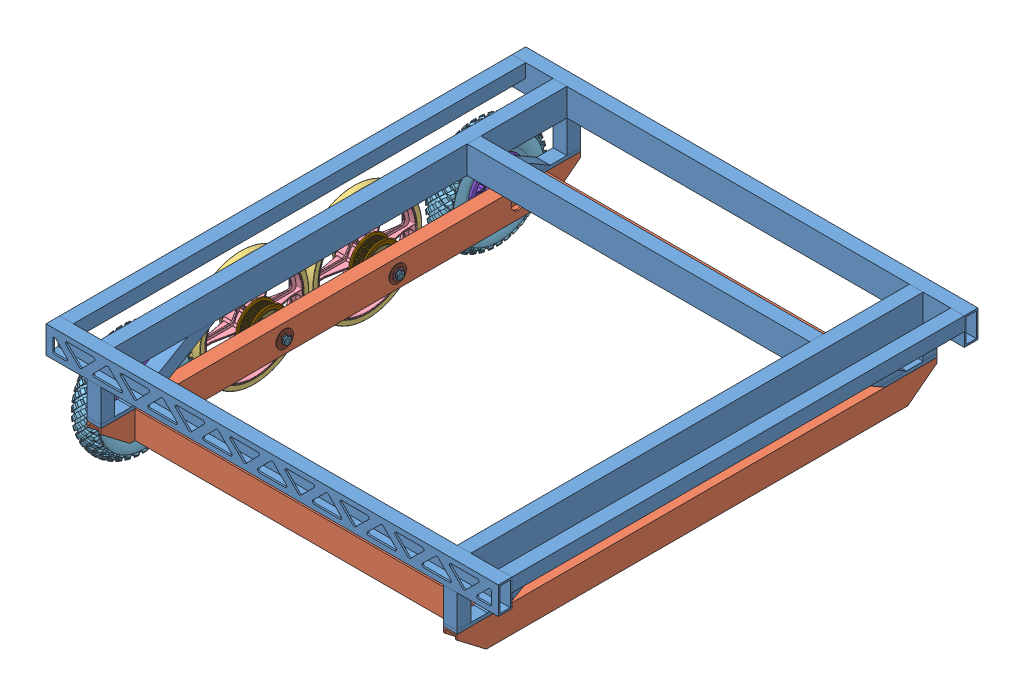
SolidWorks assembly Assem1, configuration Default. Lengths in mm.
Overall size (838.2 282.45 889).
61 component instances, 15 part files, 87 mates.
Components (placement in the parent):
- Frame-1: Frame [Default<As Machined>] at origin size (838.2 117.47 889)
- Frame_Lower-1: Frame_Lower [Default<As Machined>] at (0 -117.475 0) size (685.8 50.8 889)
- 8Inch_Wheel-1: 8Inch_Wheel [Default] at (-372.5037 -117.475 -104.775) x (0 -0.866025 -0.5) z (-1 0 0) size (204.35 204.35 38.11)
  - 2010 8 tread-1: 2010 8 tread [Default] at (0 0 12.7) size (204.35 204.35 25.4)
  - 2010 8 hub-1: 2010 8 hub [Default] at origin size (190.5 190.5 38.11)
- 8Inch_Pneumatic_Wheel-1: 8Inch_Pneumatic_Wheel [Default] at (-363.7926 -119.2955 -326.2593) x (1 0 0) z (0 1 0) size (54.46 203.4 203.4)
  - Tire-1: Tire [Default] at (-14.0642 3.9407 4.9955) x (0 0 1) z (-1 0 0) size (203.4 203.4 50.81)
  - Valve-1: Valve [Default] at (-14.5404 48.2951 4.9955) x (0 1 0) z (0 0 1) size (16.51 34.98 12.8)
  - Pneumatic Hub-1: Pneumatic Hub [Default] at (-8.6594 5.0758 -4.0835) size (45.47 106.55 106.55)
    - #4x1.00, Plastic Thread Rolling Screw, Pan Head, Cross Recessed, Zinc Plated (Plastic Applications)_-1: #4x1.00, Plastic Thread Rolling Screw, Pan Head, Cross Recessed, Zinc Plated (Plastic Applications)_ [Default] at (7.3269 34.0601 29.3991) x (-1 0 0) z (0 -0.924225 -0.381849) size (27.43 5.56 5.56)
    - Hub-1: Hub [Default] at (-28.6141 -1.1351 9.0791) size (25.79 106.55 106.55)
    - #4x1.00, Plastic Thread Rolling Screw, Pan Head, Cross Recessed, Zinc Plated (Plastic Applications)_-2: #4x1.00, Plastic Thread Rolling Screw, Pan Head, Cross Recessed, Zinc Plated (Plastic Applications)_ [Default] at (7.3269 -1.1351 -31.5609) x (-1 0 0) z (0 0.131421 0.991327) size (27.43 5.56 5.56)
    - #4x1.00, Plastic Thread Rolling Screw, Pan Head, Cross Recessed, Zinc Plated (Plastic Applications)_-3: #4x1.00, Plastic Thread Rolling Screw, Pan Head, Cross Recessed, Zinc Plated (Plastic Applications)_ [Default] at (-19.0891 -1.1351 49.7191) x (1 0 0) z (0 -0.750107 0.661316) size (27.43 5.56 5.56)
    - #4x1.00, Plastic Thread Rolling Screw, Pan Head, Cross Recessed, Zinc Plated (Plastic Applications)_-4: #4x1.00, Plastic Thread Rolling Screw, Pan Head, Cross Recessed, Zinc Plated (Plastic Applications)_ [Default] at (7.3269 -36.3304 29.3991) x (-1 0 0) z (0 0.792804 -0.609477) size (27.43 5.56 5.56)
    - #4x1.00, Plastic Thread Rolling Screw, Pan Head, Cross Recessed, Zinc Plated (Plastic Applications)_-5: #4x1.00, Plastic Thread Rolling Screw, Pan Head, Cross Recessed, Zinc Plated (Plastic Applications)_ [Default] at (-19.0891 34.0601 -11.2409) x (1 0 0) z (0 0.94777 0.318954) size (27.43 5.56 5.56)
    - #4x1.00, Plastic Thread Rolling Screw, Pan Head, Cross Recessed, Zinc Plated (Plastic Applications)_-6: #4x1.00, Plastic Thread Rolling Screw, Pan Head, Cross Recessed, Zinc Plated (Plastic Applications)_ [Default] at (-19.0891 -36.3304 -11.2409) x (1 0 0) z (0 -0.197663 -0.98027) size (27.43 5.56 5.56)
    - Hub-2: Hub [Default] at (16.8519 -1.1351 9.0791) x (-1 0 0) z (0 0 -1) size (25.79 106.55 106.55)
- 8Inch_Pneumatic_Wheel-2: 8Inch_Pneumatic_Wheel [Default] at (-359.7159 -119.2955 334.1407) x (1 0 0) z (0 1 0) size (54.46 203.4 203.4)
  - Tire-1: Tire [Default] at (-14.0642 3.9407 4.9955) x (0 0 1) z (-1 0 0) size (203.4 203.4 50.81)
  - Valve-1: Valve [Default] at (-14.5404 48.2951 4.9955) x (0 1 0) z (0 0 1) size (16.51 34.98 12.8)
  - Pneumatic Hub-1: Pneumatic Hub [Default] at (-8.6594 5.0758 -4.0835) size (45.47 106.55 106.55)
    - #4x1.00, Plastic Thread Rolling Screw, Pan Head, Cross Recessed, Zinc Plated (Plastic Applications)_-1: #4x1.00, Plastic Thread Rolling Screw, Pan Head, Cross Recessed, Zinc Plated (Plastic Applications)_ [Default] at (7.3269 34.0601 29.3991) x (-1 0 0) z (0 -0.924225 -0.381849) size (27.43 5.56 5.56)
    - Hub-1: Hub [Default] at (-28.6141 -1.1351 9.0791) size (25.79 106.55 106.55)
    - #4x1.00, Plastic Thread Rolling Screw, Pan Head, Cross Recessed, Zinc Plated (Plastic Applications)_-2: #4x1.00, Plastic Thread Rolling Screw, Pan Head, Cross Recessed, Zinc Plated (Plastic Applications)_ [Default] at (7.3269 -1.1351 -31.5609) x (-1 0 0) z (0 0.131421 0.991327) size (27.43 5.56 5.56)
    - #4x1.00, Plastic Thread Rolling Screw, Pan Head, Cross Recessed, Zinc Plated (Plastic Applications)_-3: #4x1.00, Plastic Thread Rolling Screw, Pan Head, Cross Recessed, Zinc Plated (Plastic Applications)_ [Default] at (-19.0891 -1.1351 49.7191) x (1 0 0) z (0 -0.750107 0.661316) size (27.43 5.56 5.56)
    - #4x1.00, Plastic Thread Rolling Screw, Pan Head, Cross Recessed, Zinc Plated (Plastic Applications)_-4: #4x1.00, Plastic Thread Rolling Screw, Pan Head, Cross Recessed, Zinc Plated (Plastic Applications)_ [Default] at (7.3269 -36.3304 29.3991) x (-1 0 0) z (0 0.792804 -0.609477) size (27.43 5.56 5.56)
    - #4x1.00, Plastic Thread Rolling Screw, Pan Head, Cross Recessed, Zinc Plated (Plastic Applications)_-5: #4x1.00, Plastic Thread Rolling Screw, Pan Head, Cross Recessed, Zinc Plated (Plastic Applications)_ [Default] at (-19.0891 34.0601 -11.2409) x (1 0 0) z (0 0.94777 0.318954) size (27.43 5.56 5.56)
    - #4x1.00, Plastic Thread Rolling Screw, Pan Head, Cross Recessed, Zinc Plated (Plastic Applications)_-6: #4x1.00, Plastic Thread Rolling Screw, Pan Head, Cross Recessed, Zinc Plated (Plastic Applications)_ [Default] at (-19.0891 -36.3304 -11.2409) x (1 0 0) z (0 -0.197663 -0.98027) size (27.43 5.56 5.56)
    - Hub-2: Hub [Default] at (16.8519 -1.1351 9.0791) x (-1 0 0) z (0 0 -1) size (25.79 106.55 106.55)
- 8Inch_Wheel-2: 8Inch_Wheel [Default] at (-372.5037 -117.475 104.775) x (0 -0.866025 -0.5) z (-1 0 0) size (204.35 204.35 38.11)
  - 2010 8 tread-1: 2010 8 tread [Default] at (0 0 12.7) size (204.35 204.35 25.4)
  - 2010 8 hub-1: 2010 8 hub [Default] at origin size (190.5 190.5 38.11)
- 2.6Inch_Plastic_Pulley-1: 2.6Inch_Plastic_Pulley [Default] at (-367.1697 -117.475 104.775) x (1 0 0) z (0 -0.5 0.866025) size (23.46 74.23 74.23)
  - am-2234_2.6Inch_Plastic_Pulley-1: am-2234_2.6Inch_Plastic_Pulley [Default] at origin size (13 74.23 74.23)
  - am-2234_2.6Inch_Plastic_Pulley-2: am-2234_2.6Inch_Plastic_Pulley [Default] at (16.6624 0 0) x (-1 0 0) z (0 0.000084 1) size (13 74.23 74.23)
- am-0277_16Tooth_Sprocket-1: am-0277_16Tooth_Sprocket [Default] at (-334.137 -117.475 104.775) x (0 0.811515 -0.584332) z (-1 0 0) size (35.21 35.21 10.86)
- 1.125Inch_Flange_Bearing-1: 1.125Inch_Flange_Bearing [Default] at (-315.9252 -117.475 104.775) x (0 0.899836 0.436228) z (0 -0.436228 0.899836) size (31.12 7.92 31.12)
- 1.125Inch_Flange_Bearing-2: 1.125Inch_Flange_Bearing [Default] at (-344.4748 -117.475 104.775) x (0 0.899836 -0.436228) z (0 -0.436228 -0.899836) size (31.12 7.92 31.12)
- am-0096a_Hex_Hub-1: am-0096a_Hex_Hub [Default] at (-390.3296 -117.475 104.775) size (25.4 57.15 57.15)
- 1.125Inch_Flange_Bearing-3: 1.125Inch_Flange_Bearing [Default] at (-315.9252 -117.475 -104.775) x (0 0.899836 0.436228) z (0 -0.436228 0.899836) size (31.12 7.92 31.12)
- am-0277_16Tooth_Sprocket-2: am-0277_16Tooth_Sprocket [Default] at (-334.137 -117.475 -104.775) x (0 0.911804 0.410626) z (-1 0 0) size (35.21 35.21 10.86)
- 1.125Inch_Flange_Bearing-4: 1.125Inch_Flange_Bearing [Default] at (-344.4748 -117.475 -104.775) x (0 0.072133 -0.997395) z (0 -0.997395 -0.072133) size (31.12 7.92 31.12)
- am-0096a_Hex_Hub-2: am-0096a_Hex_Hub [Default] at (-365.4474 -117.475 -104.775) x (-1 0 0) z (0 0 -1) size (25.4 57.15 57.15)
- 2.6Inch_Plastic_Pulley-2: 2.6Inch_Plastic_Pulley [Default] at (-367.1697 -117.4742 -104.7754) x (1 0 0) z (0 -0.500018 0.866015) size (23.46 74.23 74.23)
  - am-2234_2.6Inch_Plastic_Pulley-1: am-2234_2.6Inch_Plastic_Pulley [Default] at origin size (13 74.23 74.23)
  - am-2234_2.6Inch_Plastic_Pulley-2: am-2234_2.6Inch_Plastic_Pulley [Default] at (16.6624 0 0) x (-1 0 0) z (0 0.000084 1) size (13 74.23 74.23)
- 0.5Inch_Hex_Bearing_Washer-1: 0.5Inch_Hex_Bearing_Washer [Default] at (-346.0623 -117.475 -104.775) x (0 -0.5 0.866025) z (1 0 0) size (19.51 19.51 1.59)
- am-0096a_Hex_Hub-3: am-0096a_Hex_Hub [Default] at (-390.3296 -117.475 -104.775) x (1 0 0) z (0 0.866025 0.5) size (25.4 57.15 57.15)
- 5Inch_Hex_Shaft-2: 5Inch_Hex_Shaft [Default] at (-310.3372 -117.475 -104.775) x (0 -1 0) z (-1 0 0) size (14.66 12.7 103.19)
- 0.5Inch_Hex_Bearing_Washer-2: 0.5Inch_Hex_Bearing_Washer [Default] at (-315.9252 -117.475 -104.775) x (0 1 0) z (1 0 0) size (19.51 19.51 1.59)
- am-0096a_Hex_Hub-4: am-0096a_Hex_Hub [Default] at (-365.4474 -117.475 104.775) x (-1 0 0) z (0 -0.866025 -0.5) size (25.4 57.15 57.15)
- 0.5Inch_Hex_Bearing_Washer-3: 0.5Inch_Hex_Bearing_Washer [Default] at (-346.0623 -117.475 104.775) x (0 1 0) z (1 0 0) size (19.51 19.51 1.59)
- 5Inch_Hex_Shaft-3: 5Inch_Hex_Shaft [Default] at (-310.3372 -117.475 104.775) x (0 -1 0) z (-1 0 0) size (14.66 12.7 103.19)
- 5Inch_Hex_Shaft-4: 5Inch_Hex_Shaft [Default] at (-303.0728 -114.3 330.2) x (0 0.866025 0.5) z (-1 0 0) size (14.66 12.7 103.19)
- 1.125Inch_Flange_Bearing-5: 1.125Inch_Flange_Bearing [Default] at (-315.9252 -114.3 330.2) x (0 0.997395 -0.072133) z (0 0.072133 0.997395) size (31.12 7.92 31.12)
- am-0277_16Tooth_Sprocket-3: am-0277_16Tooth_Sprocket [Default] at (-334.137 -114.3 330.2) x (0 -0.584332 -0.811515) z (-1 0 0) size (35.21 35.21 10.86)
- 1.125Inch_Flange_Bearing-6: 1.125Inch_Flange_Bearing [Default] at (-344.4748 -114.3 330.2) x (0 -0.436228 -0.899836) z (0 -0.899836 0.436228) size (31.12 7.92 31.12)
- am-0096a_Hex_Hub-5: am-0096a_Hex_Hub [Default] at (-365.4474 -114.3 330.2) x (-1 0 0) z (0 -1 0) size (25.4 57.15 57.15)
- 0.5Inch_Hex_Bearing_Washer-4: 0.5Inch_Hex_Bearing_Washer [Default] at (-346.0623 -114.3 330.2) x (0 0 -1) z (1 0 0) size (19.51 19.51 1.59)
- am-0096a_Hex_Hub-6: am-0096a_Hex_Hub [Default] at (-383.0652 -114.3 330.2) x (1 0 0) z (0 0.5 0.866025) size (25.4 57.15 57.15)
- Floor-3: Floor [Default] at (-723.9922 -221.615 867.1926) size (1524 2.54 1524) (hidden)
Mates (geometry in assembly coordinates):
- Coincident1: coincident anti-aligned: plane of Frame-1 through (317.5 -92.075 368.3) normal (0 -1 0); plane of Frame_Lower-1 through (317.5 -92.075 -444.5) normal (0 1 0)
- Coincident2: coincident aligned: plane of Frame-1 through (342.9 -88.9 419.1) normal (1 0 0); plane of Frame_Lower-1 through (342.9 -142.875 -444.5) normal (1 0 0)
- Coincident3: coincident aligned: plane of Frame-1 through (317.5 -88.9 444.5) normal (0 0 1); plane of Frame_Lower-1 through (660.4 -117.475 444.5) normal (0 0 1)
- Concentric1: concentric anti-aligned: circle of Frame_Lower-1; line of 8Inch_Pneumatic_Wheel-1 through (-295.8595 -114.3 -330.2) axis (-1 0 0)
- Distance3: distance = 12.7 mm anti-aligned: plane of 8Inch_Pneumatic_Wheel-1/Pneumatic Hub-1/Hub-2 through (-355.6 -114.3 -330.2) normal (1 0 0); plane of Frame_Lower-1 through (-342.9 -142.875 -444.5) normal (-1 0 0)
- Parallel3: parallel aligned: plane of Frame_Lower-1 through (-342.9 -142.875 -444.5) normal (0 -1 0); plane of 8Inch_Pneumatic_Wheel-1
- Parallel4: parallel aligned: plane of Frame_Lower-1 through (-342.9 -142.875 -444.5) normal (0 -1 0); plane of 8Inch_Wheel-1/2010 8 hub-1
- Concentric2: concentric aligned: circle of Frame_Lower-1; line of 8Inch_Wheel-1/2010 8 hub-1 through (-446.6575 -117.475 -104.775) axis (1 0 0)
- Concentric3: concentric anti-aligned: circle of Frame_Lower-1; line of 8Inch_Pneumatic_Wheel-2 through (-291.7828 -114.3 330.2) axis (-1 0 0)
- Parallel5: parallel aligned: plane of Frame_Lower-1 through (-342.9 -142.875 -444.5) normal (0 -1 0); plane of 8Inch_Pneumatic_Wheel-2
- Concentric4: concentric aligned: circle of Frame_Lower-1; line of 8Inch_Wheel-2/2010 8 hub-1 through (-446.6575 -117.475 104.775) axis (1 0 0)
- Concentric5: concentric aligned: circle of Frame_Lower-1; line of 2.6Inch_Plastic_Pulley-1/am-2234_2.6Inch_Plastic_Pulley-1 through (-400.6806 -117.475 104.775) axis (1 0 0)
- Parallel6: parallel aligned: plane of Frame_Lower-1 through (-342.9 -142.875 -444.5) normal (0 -1 0); plane of 8Inch_Wheel-2/2010 8 hub-1
- Concentric6: concentric aligned: circle of 8Inch_Wheel-2/2010 8 hub-1; circle of 2.6Inch_Plastic_Pulley-1/am-2234_2.6Inch_Plastic_Pulley-1
- Coincident5: coincident anti-aligned: plane of 8Inch_Wheel-2/2010 8 hub-1 through (-366.1537 -117.475 104.775) normal (1 0 0); plane of 2.6Inch_Plastic_Pulley-1/am-2234_2.6Inch_Plastic_Pulley-1 through (-366.1537 -117.475 104.775) normal (-1 0 0)
- Concentric7: concentric anti-aligned: circle of Frame_Lower-1; line of am-0277_16Tooth_Sprocket-1 through (-298.8776 -117.475 104.775) axis (-1 0 0)
- Concentric8: concentric aligned: circle of Frame_Lower-1; line of 1.125Inch_Flange_Bearing-1 through (-343.7828 -117.475 104.775) axis (1 0 0)
- Coincident6: coincident anti-aligned: plane of Frame_Lower-1 through (-317.5 -142.875 -444.5) normal (1 0 0); plane of 1.125Inch_Flange_Bearing-1 through (-317.5 -117.475 104.775) normal (-1 0 0)
- Coincident7: coincident anti-aligned: plane of am-0277_16Tooth_Sprocket-1 through (-323.85 -117.475 104.775) normal (1 0 0); plane of 1.125Inch_Flange_Bearing-1 through (-323.85 -117.475 104.775) normal (-1 0 0)
- Concentric9: concentric anti-aligned: circle of Frame_Lower-1; line of 1.125Inch_Flange_Bearing-2 through (-316.6172 -117.475 104.775) axis (-1 0 0)
- Coincident8: coincident anti-aligned: plane of Frame_Lower-1 through (-342.9 -142.875 -444.5) normal (-1 0 0); plane of 1.125Inch_Flange_Bearing-2 through (-342.9 -117.475 104.775) normal (1 0 0)
- Parallel7: parallel anti-aligned: line of am-0277_16Tooth_Sprocket-1 through (-334.137 -112.6755 109.162) axis (0 -0.5 0.866025); line of 1.125Inch_Flange_Bearing-1 through (-315.9252 -113.8088 111.125) axis (0 0.5 -0.866025)
- Parallel8: parallel anti-aligned: line of 1.125Inch_Flange_Bearing-1 through (-315.9252 -113.8088 111.125) axis (0 0.5 -0.866025); line of 1.125Inch_Flange_Bearing-2 through (-336.55 -110.1427 104.775) axis (0 -0.5 0.866025)
- Concentric10: concentric anti-aligned: circle of Frame_Lower-1; line of am-0096a_Hex_Hub-1 through (-361.0779 -117.475 104.775) axis (-1 0 0)
- Coincident9: coincident anti-aligned: plane of 8Inch_Wheel-2/2010 8 hub-1 through (-404.2537 -117.475 104.775) normal (-1 0 0); plane of am-0096a_Hex_Hub-1 through (-404.2537 -117.475 110.5014) normal (1 0 0)
- Concentric11: concentric anti-aligned: circle of 8Inch_Wheel-2/2010 8 hub-1; circle of am-0096a_Hex_Hub-1
- Parallel9: parallel aligned: line of 1.125Inch_Flange_Bearing-2 through (-344.4748 -110.1427 104.775) axis (0 -0.5 0.866025); line of am-0096a_Hex_Hub-1 through (-409.7147 -110.1133 104.775) axis (0 -0.5 0.866025)
- Concentric13: concentric aligned: circle of Frame_Lower-1; line of 1.125Inch_Flange_Bearing-3 through (-343.7828 -117.475 -104.775) axis (1 0 0)
- Coincident14: coincident anti-aligned: plane of Frame_Lower-1 through (-317.5 -142.875 -444.5) normal (1 0 0); plane of 1.125Inch_Flange_Bearing-3 through (-317.5 -117.475 -104.775) normal (-1 0 0)
- Concentric14: concentric anti-aligned: circle of Frame_Lower-1; line of am-0277_16Tooth_Sprocket-2 through (-298.8776 -117.475 -104.775) axis (-1 0 0)
- Coincident15: coincident anti-aligned: plane of 1.125Inch_Flange_Bearing-3 through (-323.85 -117.475 -104.775) normal (-1 0 0); plane of am-0277_16Tooth_Sprocket-2 through (-323.85 -117.475 -104.775) normal (1 0 0)
- Concentric15: concentric anti-aligned: circle of Frame_Lower-1; line of 1.125Inch_Flange_Bearing-4 through (-316.6172 -117.475 -104.775) axis (-1 0 0)
- Coincident16: coincident anti-aligned: plane of Frame_Lower-1 through (-342.9 -142.875 -444.5) normal (-1 0 0); plane of 1.125Inch_Flange_Bearing-4 through (-342.9 -117.475 -104.775) normal (1 0 0)
- Parallel11: parallel anti-aligned: line of 1.125Inch_Flange_Bearing-3 through (-315.9252 -121.1412 -111.125) axis (0 -0.5 0.866025); line of am-0277_16Tooth_Sprocket-2 through (-334.137 -122.2745 -109.162) axis (0 0.5 -0.866025)
- Parallel12: parallel anti-aligned: line of 1.125Inch_Flange_Bearing-3 through (-315.9252 -121.1412 -111.125) axis (0 -0.5 0.866025); line of 1.125Inch_Flange_Bearing-4 through (-336.55 -124.8073 -104.775) axis (0 0.5 -0.866025)
- Concentric16: concentric aligned: circle of Frame_Lower-1; line of am-0096a_Hex_Hub-2 through (-394.6991 -117.475 -104.775) axis (1 0 0)
- Parallel13: parallel aligned: line of 1.125Inch_Flange_Bearing-4 through (-344.4748 -121.1412 -98.425) axis (0 -0.5 -0.866025); line of am-0096a_Hex_Hub-2 through (-371.4623 -121.1559 -98.3996) axis (0 -0.5 -0.866025)
- Concentric17: concentric aligned: circle of 8Inch_Wheel-1/2010 8 hub-1; circle of am-0096a_Hex_Hub-2
- Concentric18: concentric aligned: circle of Frame_Lower-1; line of 2.6Inch_Plastic_Pulley-2/am-2234_2.6Inch_Plastic_Pulley-1 through (-400.6806 -117.4743 -104.7754) axis (1 0 0)
- Concentric19: concentric anti-aligned: circle of am-0096a_Hex_Hub-2; circle of 2.6Inch_Plastic_Pulley-2/am-2234_2.6Inch_Plastic_Pulley-2
- Coincident18: coincident anti-aligned: plane of am-0096a_Hex_Hub-2 through (-351.5233 -117.475 -110.5014) normal (-1 0 0); plane of 2.6Inch_Plastic_Pulley-2/am-2234_2.6Inch_Plastic_Pulley-2 through (-351.5233 -117.4743 -104.7754) normal (1 0 0)
- Coincident19: coincident anti-aligned: plane of 8Inch_Wheel-1/2010 8 hub-1 through (-366.1537 -117.475 -104.775) normal (1 0 0); plane of 2.6Inch_Plastic_Pulley-2/am-2234_2.6Inch_Plastic_Pulley-1 through (-366.1537 -117.4742 -104.7754) normal (-1 0 0)
- Concentric20: concentric anti-aligned: circle of Frame_Lower-1; line of 0.5Inch_Hex_Bearing_Washer-1 through (-330.9668 -117.475 -104.775) axis (-1 0 0)
- Coincident20: coincident anti-aligned: plane of 1.125Inch_Flange_Bearing-4 through (-344.4748 -117.475 -104.775) normal (-1 0 0); plane of 0.5Inch_Hex_Bearing_Washer-1 through (-344.4748 -117.475 -104.775) normal (1 0 0)
- Parallel14: parallel aligned: line of 1.125Inch_Flange_Bearing-4 through (-344.4748 -121.1412 -98.425) axis (0 -0.5 -0.866025); line of 0.5Inch_Hex_Bearing_Washer-1 through (-346.0623 -121.2145 -98.298) axis (0 -0.5 -0.866025)
- Coincident21: coincident anti-aligned: plane of am-0096a_Hex_Hub-2 through (-346.0623 -117.475 -104.775) normal (1 0 0); plane of 0.5Inch_Hex_Bearing_Washer-1 through (-346.0623 -117.475 -104.775) normal (-1 0 0)
- Concentric21: concentric aligned: cylinder of 8Inch_Wheel-1/2010 8 hub-1 through (-404.2537 -117.475 -104.775) axis (-1 0 0) radius 14.2812; line of am-0096a_Hex_Hub-3 through (-361.0779 -117.475 -104.775) axis (-1 0 0)
- Parallel15: parallel aligned: line of am-0096a_Hex_Hub-2 through (-371.4623 -113.7942 -98.3996) axis (0 -1 0); line of am-0096a_Hex_Hub-3 through (-409.7147 -113.7942 -98.3996) axis (0 -1 0)
- Coincident22: coincident anti-aligned: plane of 8Inch_Wheel-1/2010 8 hub-1 through (-404.2537 -117.475 -104.775) normal (-1 0 0); plane of am-0096a_Hex_Hub-3 through (-404.2537 -112.5158 -101.9118) normal (1 0 0)
- Concentric22: concentric aligned: cylinder of am-0096a_Hex_Hub-3 through (-403.3647 -117.475 -104.775) axis (-1 0 0) radius 28.575; line of 5Inch_Hex_Shaft-2 through (-275.6349 -117.475 -104.775) axis (-1 0 0)
- Coincident23: coincident aligned: plane of am-0096a_Hex_Hub-3 through (-409.7147 -117.475 -104.775) normal (-1 0 0); plane of 5Inch_Hex_Shaft-2 through (-409.7147 -117.475 -104.775) normal (-1 0 0)
- Parallel16: parallel anti-aligned: line of am-0096a_Hex_Hub-3 through (-409.7147 -113.7942 -111.1504) axis (0 0.5 0.866025); line of 5Inch_Hex_Shaft-2 through (-409.7147 -110.1427 -104.775) axis (0 -0.5 -0.866025)
- Concentric23: concentric anti-aligned: cylinder of 5Inch_Hex_Shaft-2 through (-335.7372 -117.475 -104.775) axis (1 0 0) radius 2.54; line of 0.5Inch_Hex_Bearing_Washer-2 through (-300.8297 -117.475 -104.775) axis (-1 0 0)
- Coincident24: coincident anti-aligned: plane of 1.125Inch_Flange_Bearing-3 through (-315.9252 -117.475 -104.775) normal (1 0 0); plane of 0.5Inch_Hex_Bearing_Washer-2 through (-315.9252 -117.475 -104.775) normal (-1 0 0)
- Parallel17: parallel aligned: line of 5Inch_Hex_Shaft-2 through (-310.3372 -113.8088 -98.425) axis (0 0.5 -0.866025); line of 0.5Inch_Hex_Bearing_Washer-2 through (-314.3377 -124.954 -104.775) axis (0 0.5 -0.866025)
- Concentric24: concentric aligned: circle of Frame_Lower-1; line of am-0096a_Hex_Hub-4 through (-394.6991 -117.475 104.775) axis (1 0 0)
- Coincident25: coincident anti-aligned: plane of 2.6Inch_Plastic_Pulley-1/am-2234_2.6Inch_Plastic_Pulley-2 through (-351.5233 -117.475 104.775) normal (1 0 0); plane of am-0096a_Hex_Hub-4 through (-351.5233 -122.4342 101.9118) normal (-1 0 0)
- Concentric25: concentric anti-aligned: circle of 2.6Inch_Plastic_Pulley-1/am-2234_2.6Inch_Plastic_Pulley-2; circle of am-0096a_Hex_Hub-4
- Coincident26: coincident anti-aligned: plane of am-0096a_Hex_Hub-4 through (-346.0623 -117.475 104.775) normal (1 0 0); plane of 0.5Inch_Hex_Bearing_Washer-3 through (-346.0623 -117.475 104.775) normal (-1 0 0)
- Concentric26: concentric anti-aligned: circle of Frame_Lower-1; line of 0.5Inch_Hex_Bearing_Washer-3 through (-330.9668 -117.475 104.775) axis (-1 0 0)
- Coincident27: coincident anti-aligned: plane of 1.125Inch_Flange_Bearing-2 through (-344.4748 -117.475 104.775) normal (-1 0 0); plane of 0.5Inch_Hex_Bearing_Washer-3 through (-344.4748 -117.475 104.775) normal (1 0 0)
- Concentric27: concentric anti-aligned: circle of Frame_Lower-1; line of 5Inch_Hex_Shaft-3 through (-275.6349 -117.475 104.775) axis (-1 0 0)
- Parallel18: parallel anti-aligned: line of 5Inch_Hex_Shaft-3 through (-413.5247 -110.1427 104.775) axis (0 -0.5 -0.866025); line of am-0096a_Hex_Hub-1 through (-409.7147 -113.7942 98.3996) axis (0 0.5 0.866025)
- Coincident28: coincident aligned: plane of am-0096a_Hex_Hub-1 through (-409.7147 -117.475 104.775) normal (-1 0 0); plane of 5Inch_Hex_Shaft-3 through (-409.7147 -117.475 104.775) normal (-1 0 0)
- Concentric28: concentric anti-aligned: circle of Frame_Lower-1; line of 5Inch_Hex_Shaft-4 through (-268.3705 -114.3 330.2) axis (-1 0 0)
- Concentric29: concentric aligned: line of 1.125Inch_Flange_Bearing-5 through (-343.7828 -114.3 330.2) axis (1 0 0); circle of Frame_Lower-1
- Coincident29: coincident anti-aligned: plane of Frame_Lower-1 through (-317.5 -142.875 -444.5) normal (1 0 0); plane of 1.125Inch_Flange_Bearing-5 through (-317.5 -114.3 330.2) normal (-1 0 0)
- Concentric30: concentric anti-aligned: circle of Frame_Lower-1; line of am-0277_16Tooth_Sprocket-3 through (-298.8776 -114.3 330.2) axis (-1 0 0)
- Parallel19: parallel anti-aligned: line of 5Inch_Hex_Shaft-4 through (-306.8828 -114.3 322.8677) axis (0 -0.866025 0.5); line of am-0277_16Tooth_Sprocket-3 through (-323.85 -120.65 326.5338) axis (0 0.866025 -0.5)
- Coincident30: coincident anti-aligned: plane of 1.125Inch_Flange_Bearing-5 through (-323.85 -114.3 330.2) normal (-1 0 0); plane of am-0277_16Tooth_Sprocket-3 through (-323.85 -114.3 330.2) normal (1 0 0)
- Parallel20: parallel anti-aligned: line of 1.125Inch_Flange_Bearing-5 through (-315.9252 -120.65 333.8662) axis (0 0.866025 0.5); line of am-0277_16Tooth_Sprocket-3 through (-323.85 -114.3 337.5323) axis (0 -0.866025 -0.5)
- Concentric31: concentric anti-aligned: circle of Frame_Lower-1; line of 1.125Inch_Flange_Bearing-6 through (-316.6172 -114.3 330.2) axis (-1 0 0)
- Coincident31: coincident anti-aligned: plane of Frame_Lower-1 through (-342.9 -142.875 -444.5) normal (-1 0 0); plane of 1.125Inch_Flange_Bearing-6 through (-342.9 -114.3 330.2) normal (1 0 0)
- Parallel21: parallel anti-aligned: line of 5Inch_Hex_Shaft-4 through (-402.4503 -114.3 322.8677) axis (0 -0.866025 0.5); line of 1.125Inch_Flange_Bearing-6 through (-344.4748 -120.65 326.5338) axis (0 0.866025 -0.5)
- Concentric32: concentric aligned: circle of Frame_Lower-1; line of am-0096a_Hex_Hub-5 through (-394.6991 -114.3 330.2) axis (1 0 0)
- Parallel22: parallel aligned: line of 5Inch_Hex_Shaft-4 through (-402.4503 -107.95 326.5338) axis (0 -0.866025 -0.5); line of am-0096a_Hex_Hub-5 through (-371.4623 -114.3 337.5617) axis (0 -0.866025 -0.5)
- Concentric33: concentric anti-aligned: circle of am-0096a_Hex_Hub-5; circle of 0.5Inch_Hex_Bearing_Washer-4
- Parallel23: parallel anti-aligned: line of 5Inch_Hex_Shaft-4 through (-402.4503 -107.95 326.5338) axis (0 -0.866025 -0.5); line of 0.5Inch_Hex_Bearing_Washer-4 through (-346.0623 -114.3 322.721) axis (0 0.866025 0.5)
- Coincident32: coincident anti-aligned: plane of 1.125Inch_Flange_Bearing-6 through (-344.4748 -114.3 330.2) normal (-1 0 0); plane of 0.5Inch_Hex_Bearing_Washer-4 through (-344.4748 -114.3 330.2) normal (1 0 0)
- Coincident33: coincident anti-aligned: plane of am-0096a_Hex_Hub-5 through (-346.0623 -114.3 330.2) normal (1 0 0); plane of 0.5Inch_Hex_Bearing_Washer-4 through (-346.0623 -114.3 330.2) normal (-1 0 0)
- Coincident34: coincident anti-aligned: plane of 8Inch_Pneumatic_Wheel-2/Pneumatic Hub-1/Hub-2 through (-351.5233 -114.3 330.2) normal (1 0 0); plane of am-0096a_Hex_Hub-5 through (-351.5233 -120.0264 330.2) normal (-1 0 0)
- Concentric34: concentric anti-aligned: cylinder of am-0096a_Hex_Hub-5 through (-352.4123 -114.3 330.2) axis (1 0 0) radius 28.575; cylinder of am-0096a_Hex_Hub-6 through (-396.1003 -114.3 330.2) axis (-1 0 0) radius 28.575
- Parallel24: parallel aligned: line of 5Inch_Hex_Shaft-4 through (-402.4503 -114.3 322.8677) axis (0 -0.866025 0.5); line of am-0096a_Hex_Hub-6 through (-402.4503 -107.9246 333.8808) axis (0 -0.866025 0.5)
- Coincident35: coincident anti-aligned: plane of 8Inch_Pneumatic_Wheel-2/Pneumatic Hub-1/Hub-1 through (-396.9893 -114.3 330.2) normal (-1 0 0); plane of am-0096a_Hex_Hub-6 through (-396.9893 -111.4368 335.1592) normal (1 0 0)
- Concentric36: concentric aligned: cylinder of 8Inch_Pneumatic_Wheel-2/Pneumatic Hub-1/Hub-1 through (-373.8936 -90.4875 330.2) axis (-1 0 0) radius 2.54; circle of am-0096a_Hex_Hub-6
- Coincident36: coincident aligned: plane of 5Inch_Hex_Shaft-4 through (-402.4503 -114.3 330.2) normal (-1 0 0); plane of am-0096a_Hex_Hub-6 through (-402.4503 -114.3 330.2) normal (-1 0 0)
- Coincident38: coincident anti-aligned: plane of 8Inch_Wheel-2/2010 8 hub-1; plane of Floor-3 through (-723.9922 -219.075 867.1926) normal (0 1 0)
